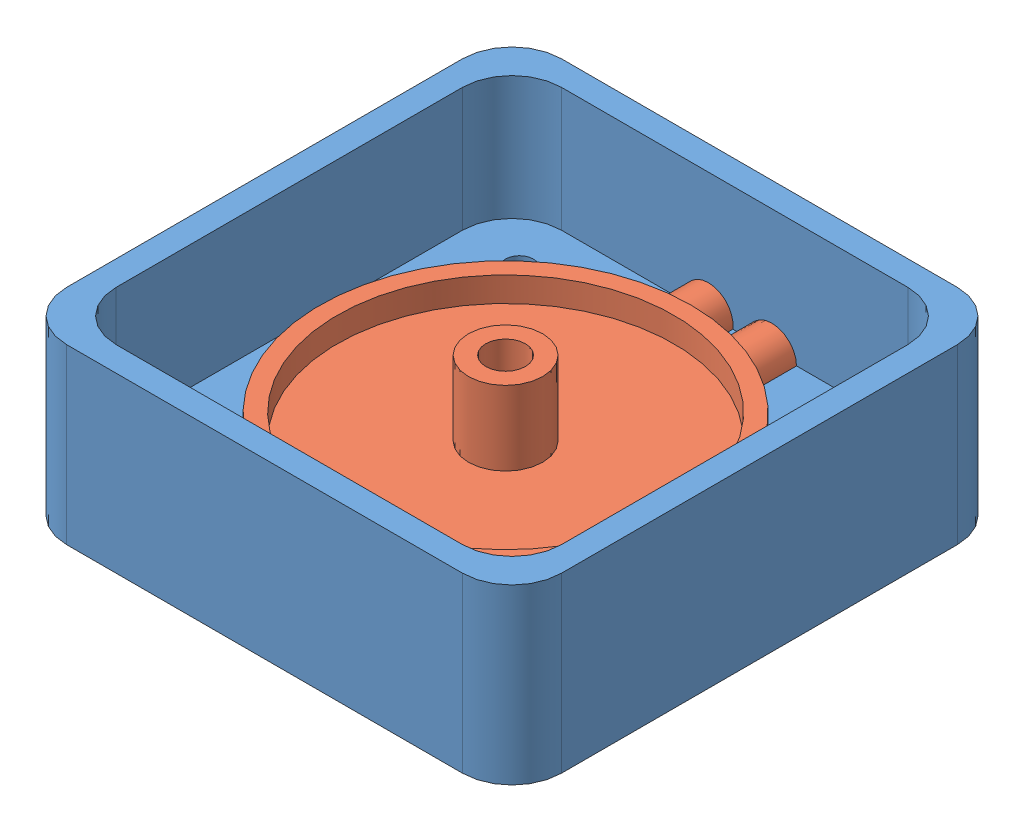
SolidWorks assembly Mold_part_1, configuration Default. Lengths in mm.
Overall size (100 35 100).
2 component instances, 2 part files, 2 mates.
Components (placement in the parent):
- mold_box-1: mold_box [Default] at (56.1752 41.4095 67.3399) size (100 35 100)
- Body3-1: Body3 [Default] at (57.3791 41.4095 69.8399) size (75 20.35 85)
Mates (geometry in assembly coordinates):
- Coincident1: coincident anti-aligned: plane of mold_box-1 through (21.1752 51.4095 32.3399) normal (0 1 0); plane of Body3-1 through (57.3791 51.4095 69.8399) normal (0 -1 0)
- Coincident2: coincident anti-aligned: plane of mold_box-1 through (21.1752 51.4095 22.3399) normal (0 0 1); plane of Body3-1 through (50.8404 52.0763 22.3399) normal (0 0 -1)
